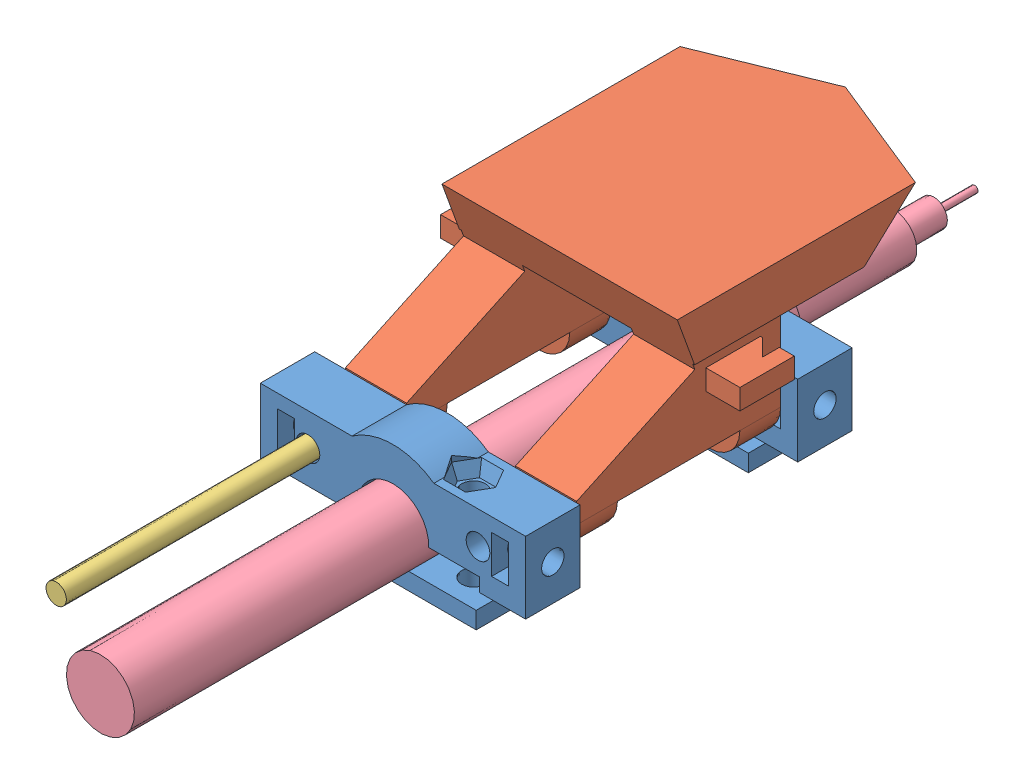
SolidWorks assembly Sliding tool, configuration Valor predeterminado. Lengths in mm.
Overall size (44 29.75 128.5).
5 component instances, 4 part files, 10 mates.
Components (placement in the parent):
- pen holder-1: pen holder [Valor predeterminado] at (-1.8551 -8.4012 42.7919) size (39 17.5 8)
- sliding tool-1: sliding tool [Valor predeterminado] at (-1.8551 14.0988 10.7919) x (1 0 0) z (0 -1 0) size (44 56.5 23.5)
- 3mm rod-1: 3mm rod [Valor predeterminado] at (-14.3551 -4.9012 2.7919) size (3 3 85)
- micron pen-1: micron pen [Valor predeterminado] at (-1.8551 -8.4012 -34.7081) x (-0.049442 0.998777 0) z (0.998777 0.049442 0) size (10 128.5 10)
- pen holder-2: pen holder [Valor predeterminado] at (-1.8551 -8.4012 2.7919) size (39 17.5 8)
Mates (geometry in assembly coordinates):
- Concêntrico1: concentric aligned: cylinder of pen holder-1 through (10.6449 -4.9012 50.7919) axis (0 0 -1) radius 1.75; cylinder of sliding tool-1 through (10.6449 -4.9012 40.7919) axis (0 0 -1) radius 1.65
- Concêntrico2: concentric aligned: cylinder of pen holder-1 through (-14.3551 -4.9012 50.7919) axis (0 0 -1) radius 1.75; cylinder of sliding tool-1 through (-14.3551 -4.9012 40.7919) axis (0 0 -1) radius 1.65
- Concêntrico3: concentric aligned: cylinder of pen holder-1 through (-14.3551 -4.9012 50.7919) axis (0 0 -1) radius 1.75; cylinder of 3mm rod-1 through (-14.3551 -4.9012 87.7919) axis (0 0 -1) radius 1.5
- Concêntrico4: concentric aligned: cylinder of pen holder-1 through (-1.8551 -8.4012 50.7919) axis (0 0 -1) radius 5.25; cylinder of micron pen-1 through (-1.8551 -8.4012 -34.7081) axis (0 0 -1) radius 5
- Concêntrico5: concentric aligned: cylinder of micron pen-1 through (-1.8551 -8.4012 -34.7081) axis (0 0 -1) radius 5; cylinder of pen holder-2 through (-1.8551 -8.4012 10.7919) axis (0 0 -1) radius 5.25
- Coincidente2: coincident aligned: plane of 3mm rod-1 through (-14.3551 -4.9012 2.7919) normal (0 0 -1); plane of pen holder-2 through (-1.8551 -8.4012 2.7919) normal (0 0 -1)
- Distância1: distance = 7 mm aligned: plane of micron pen-1 through (-2.0281 -4.9055 -4.2081) normal (0 0 -1); plane of pen holder-2 through (-1.8551 -8.4012 2.7919) normal (0 0 -1)
- Concêntrico6: concentric aligned: cylinder of 3mm rod-1 through (-14.3551 -4.9012 87.7919) axis (0 0 -1) radius 1.5; cylinder of pen holder-2 through (-14.3551 -4.9012 10.7919) axis (0 0 -1) radius 1.75
- Distância3: distance = 40 mm aligned: plane of pen holder-1 through (-1.8551 -8.4012 42.7919) normal (0 0 -1); plane of pen holder-2 through (-1.8551 -8.4012 2.7919) normal (0 0 -1)
- DistânciaLimite1: limit distance = 0 mm anti-aligned: plane of pen holder-2 through (-1.8551 -8.4012 10.7919) normal (0 0 1); plane of sliding tool-1 through (10.6449 -4.9012 10.7919) normal (0 0 -1)
